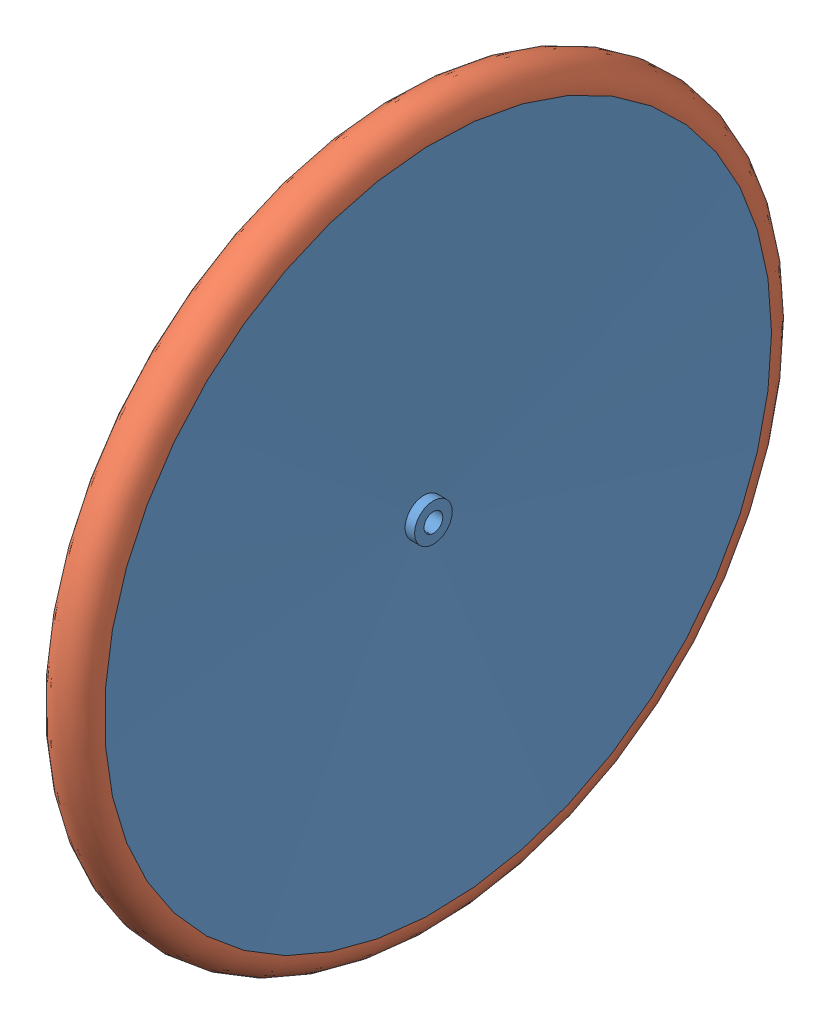
SolidWorks assembly reifen-h, configuration Standard. Lengths in mm.
Overall size (32.5 380.6 380.6).
2 component instances, 2 part files, 2 mates.
Components (placement in the parent):
- felge-h-1: felge-h [Standard] at (-81.6651 -13.0443 0) size (32.45 353.37 353.37)
- reifen-h-1: reifen-h [Standard] at (-81.6651 -13.0443 0) size (25 380.6 380.6)
Mates (geometry in assembly coordinates):
- Deckungsgleich1: coincident aligned: axis of ?; unknown of ?
- Deckungsgleich2: coincident aligned: 
